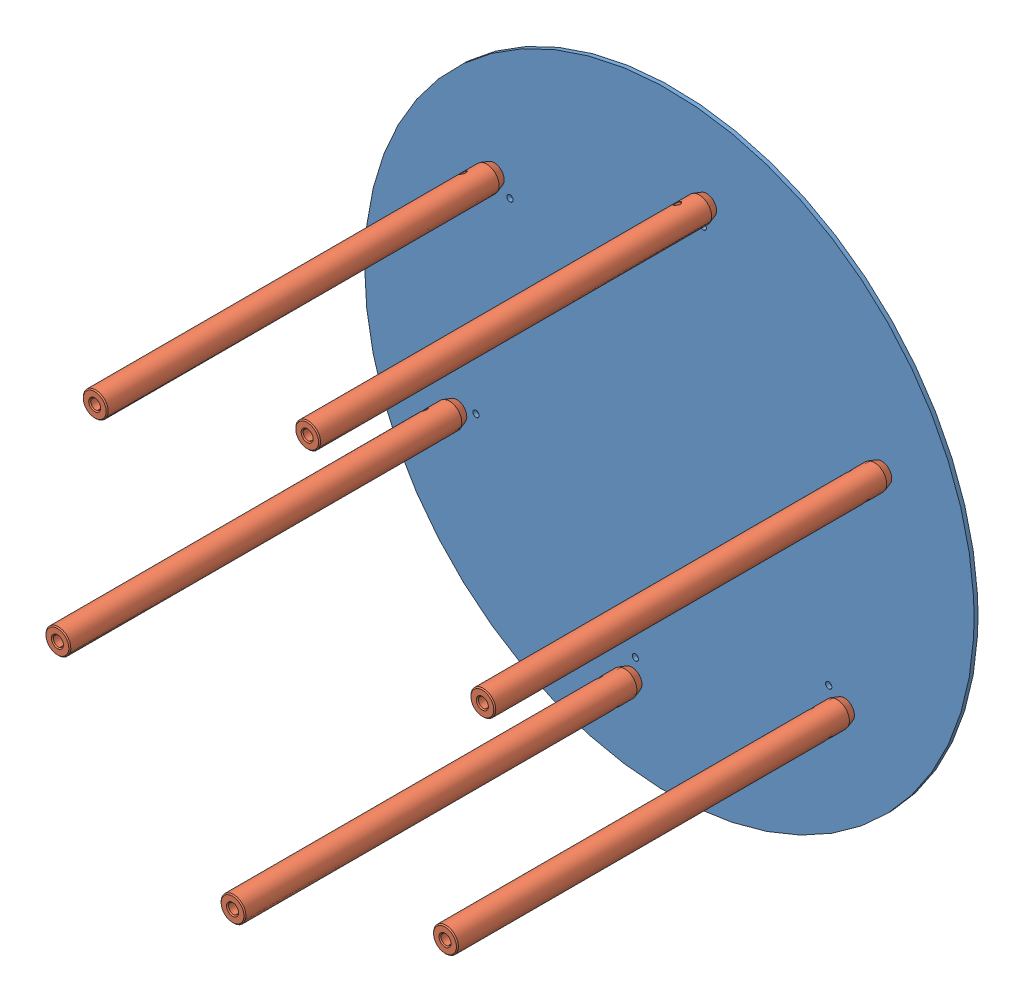
SolidWorks assembly Fixed Sample Tray Assembly, configuration Default. Lengths in mm.
Overall size (310 310 205.2).
7 component instances, 2 part files, 12 mates.
Components (placement in the parent):
- Sample Tray Fixed-1: Sample Tray Fixed [Default] at (83.4529 156.4468 279.9775) size (310 310 2)
- TR8-Solidworks-1: TR8-Solidworks [Default] at (102.4341 270.2852 485.1775) x (-0.923728 -0.383049 0) z (0.383049 -0.923728 0) size (12.67 204.86 12.87)
- TR8-Solidworks-2: TR8-Solidworks [Default] at (-5.6356 229.8137 485.1775) x (-0.85131 -0.524663 0) z (0.524663 -0.85131 0) size (12.67 204.86 12.87)
- TR8-Solidworks-3: TR8-Solidworks [Default] at (-24.6247 115.9658 485.1775) x (-0.777574 -0.628792 0) z (0.628792 -0.777574 0) size (12.67 204.86 12.87)
- TR8-Solidworks-4: TR8-Solidworks [Default] at (64.4717 42.6084 485.1775) x (-0.715577 -0.698533 0) z (0.698533 -0.715577 0) size (12.67 204.86 12.87)
- TR8-Solidworks-5: TR8-Solidworks [Default] at (172.5414 83.0799 485.1775) x (-0.676489 -0.736453 0) z (0.736453 -0.676489 0) size (12.67 204.86 12.87)
- TR8-Solidworks-6: TR8-Solidworks [Default] at (191.5304 196.9278 485.1775) x (-0.669293 -0.742999 0) z (0.742999 -0.669293 0) size (12.67 204.86 12.87)
Mates (geometry in assembly coordinates):
- Coincident1: coincident anti-aligned: plane of Sample Tray Fixed-1 through (83.4529 156.4468 281.9775) normal (0 0 1); plane of TR8-Solidworks-1 through (102.4341 270.2852 281.9775) normal (0 0 -1)
- Concentric1: concentric aligned: circle of Sample Tray Fixed-1; circle of TR8-Solidworks-1
- Coincident2: coincident anti-aligned: plane of Sample Tray Fixed-1 through (83.4529 156.4468 281.9775) normal (0 0 1); plane of TR8-Solidworks-2 through (-5.6356 229.8137 281.9775) normal (0 0 -1)
- Concentric2: concentric aligned: circle of Sample Tray Fixed-1; circle of TR8-Solidworks-2
- Coincident3: coincident anti-aligned: plane of Sample Tray Fixed-1 through (83.4529 156.4468 281.9775) normal (0 0 1); plane of TR8-Solidworks-3 through (-24.6247 115.9658 281.9775) normal (0 0 -1)
- Concentric3: concentric aligned: circle of Sample Tray Fixed-1; circle of TR8-Solidworks-3
- Coincident4: coincident anti-aligned: plane of Sample Tray Fixed-1 through (83.4529 156.4468 281.9775) normal (0 0 1); plane of TR8-Solidworks-4 through (64.4717 42.6084 281.9775) normal (0 0 -1)
- Concentric4: concentric aligned: circle of Sample Tray Fixed-1; circle of TR8-Solidworks-4
- Coincident5: coincident anti-aligned: plane of Sample Tray Fixed-1 through (83.4529 156.4468 281.9775) normal (0 0 1); plane of TR8-Solidworks-5 through (172.5414 83.0799 281.9775) normal (0 0 -1)
- Concentric5: concentric aligned: circle of Sample Tray Fixed-1; circle of TR8-Solidworks-5
- Coincident6: coincident anti-aligned: plane of Sample Tray Fixed-1 through (83.4529 156.4468 281.9775) normal (0 0 1); plane of TR8-Solidworks-6 through (191.5304 196.9278 281.9775) normal (0 0 -1)
- Concentric6: concentric aligned: circle of Sample Tray Fixed-1; circle of TR8-Solidworks-6
